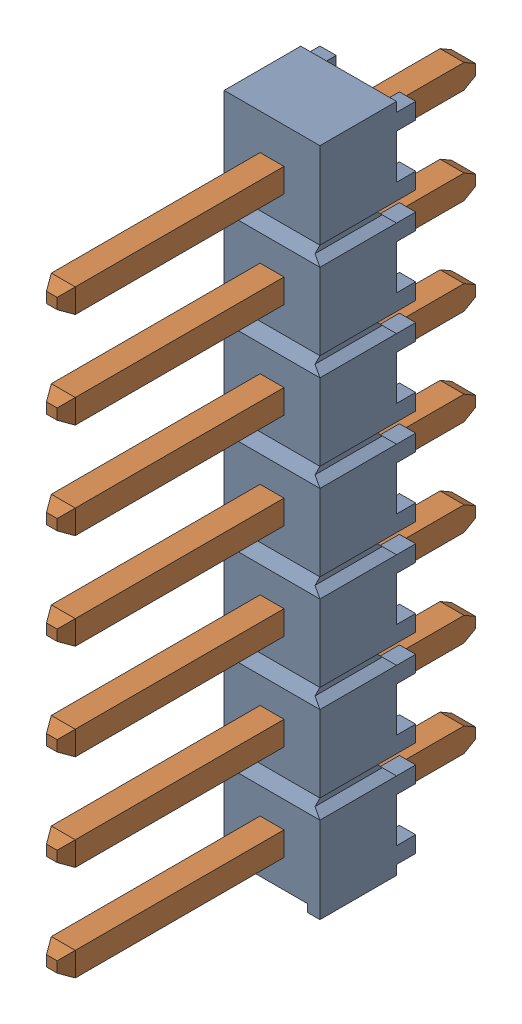
SolidWorks assembly J1PCB, configuration Default. Lengths in mm.
Overall size (2.54 17.91 10.92).
3 component instances, 2 part files, 0 mates.
Components (placement in the parent):
- TSW-107-07-G-S-1: TSW-107-07-G-S [Default] at (97.9999 106.0801 0) x (0 1 0) z (1 0 0) size (17.91 10.92 2.54)
  - _TSW-107-07-G-S_body-1: _TSW-107-07-G-S_body [Default] at origin size (17.91 2.54 2.54)
  - _T-1S6-07-TSW-1-07-7-S-1: _T-1S6-07-TSW-1-07-7-S [Default] at (0 -2.54 0) size (16.13 10.92 0.89)
